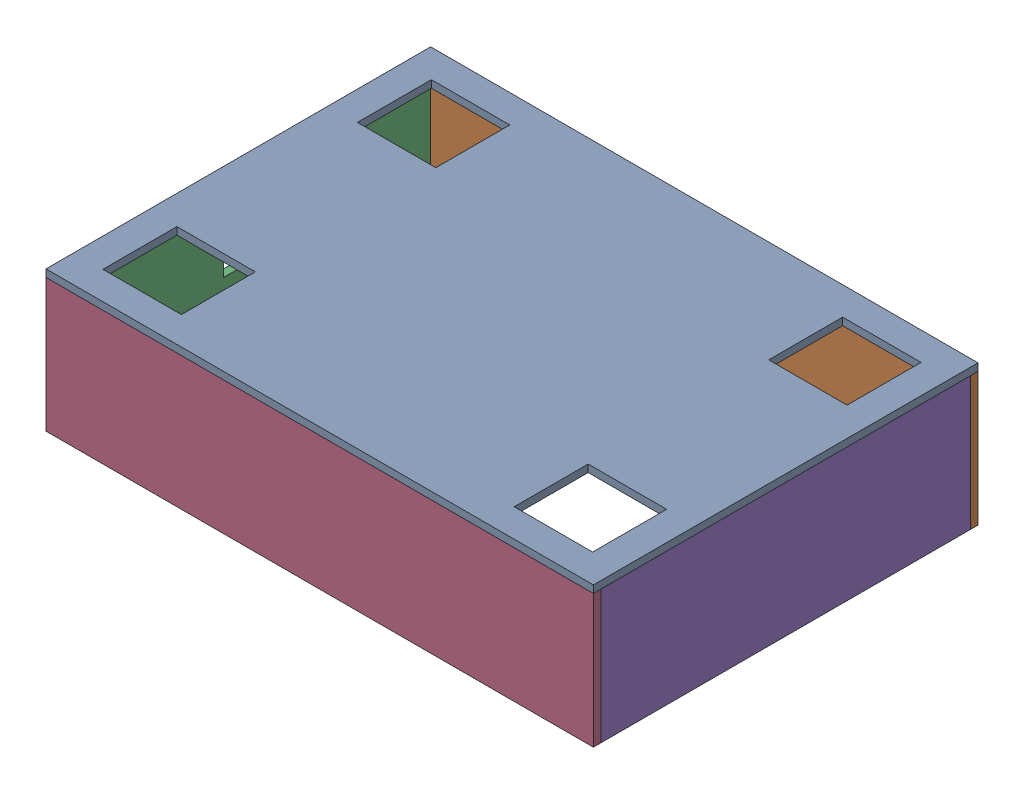
SolidWorks assembly Assem2, configuration Default. Lengths in mm.
Overall size (370 95 260).
5 component instances, 4 part files, 6 mates.
Components (placement in the parent):
- Part 1-1: Part 1 [Default] at (-14.3289 16.3656 -5.2559) size (370 5 260)
- Part2-1: Part2 [Default] at (-14.3289 -28.6344 -135.2559) size (370 90 5)
- Part4-2: Part4 [Default] at (-199.3289 -28.6344 -5.2559) size (5 90 250)
- Part2-2: Part2 [Default] at (-14.3289 -28.6344 119.7441) size (370 90 5)
- part 3-1: part 3 [Default] at (170.6711 -28.6344 -5.2559) x (0 0 -1) z (0 1 0) size (250 5 90)
Mates (geometry in assembly coordinates):
- Coincident8: coincident: Part4-2, Part2-2
- Coincident9: coincident: Part 1-1, Part2-1
- Coincident10: coincident: Part 1-1, Part2-1
- Coincident12: coincident: Part 1-1, Part4-2
- Coincident17: coincident: Part 1-1, part 3-1
- Coincident18: coincident: Part2-1, part 3-1
